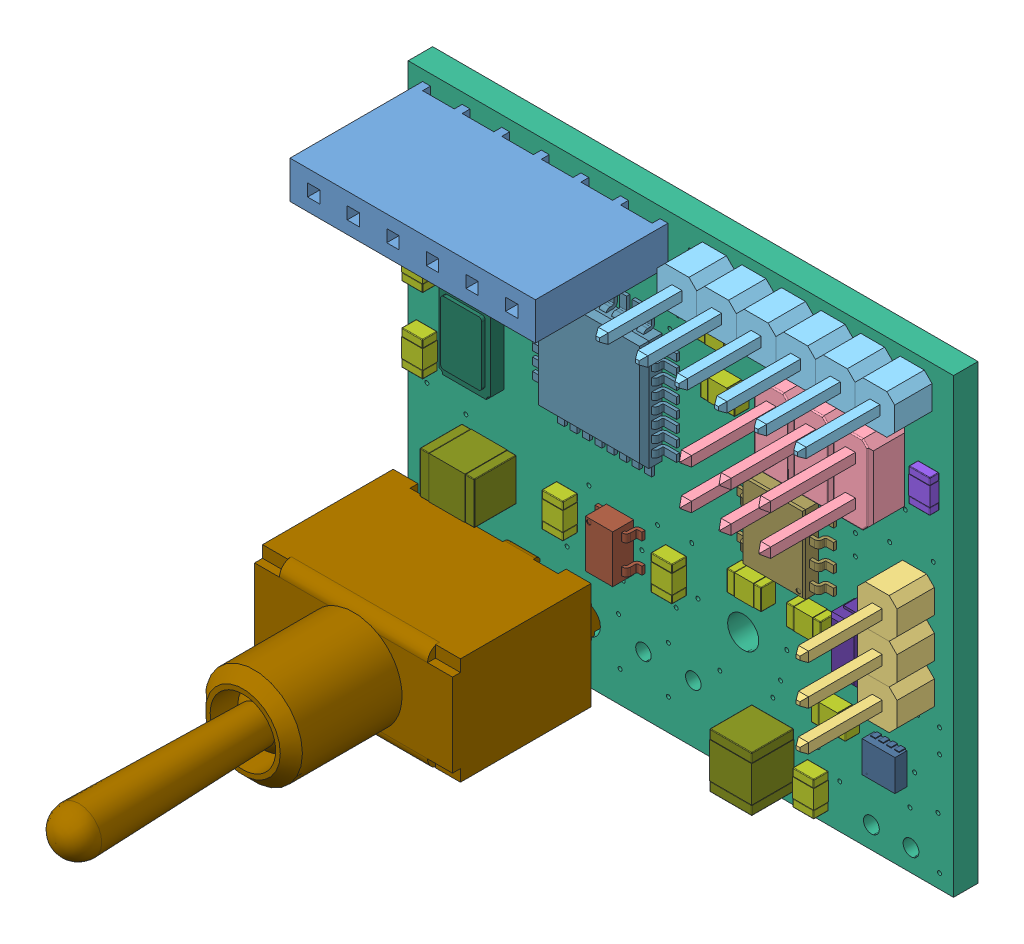
SolidWorks assembly vehicle, configuration Default. Lengths in mm.
Overall size (35 29 34.79).
44 component instances, 17 part files, 0 mates.
Components (placement in the parent):
- vehicle.step-1: vehicle.step [Default] at origin size (35 29 34.79)
  - PCB Component.step-1: PCB Component.step [Default] at origin size (35 29 34.79)
    - HM-10.step-1: HM-10.step [Default] at (8.8 27.1 1.57) x (0 1 0) z (0 0 1) size (2.41 15.75 11.15)
      - _SSW-106-01-S-S_terminal.step-1: _SSW-106-01-S-S_terminal.step [Default] x (0 -1 0) z (-1 0 0) size (15.75 8.51 2.41)
      - _SSW-106-01-S-S_pin.step-1: _SSW-106-01-S-S_pin.step [Default] at (0 0 -2.6416) x (0 -1 0) z (-1 0 0) size (13.74 3.66 1.22)
    - MG90S.step-1: MG90S.step [Default] at (32.5 13.3 1.57) x (0 -1 0) z (0 0 1) size (7.62 2.54 10.67)
      - P(B,C)C01SAAN (1).step-1: P(B,C)C01SAAN (1).step [Default] at (-2.54 0 0) x (1 0 0) z (0 -1 0) size (2.54 10.67 2.54)
      - P(B,C)C01SAAN (1).step-2: P(B,C)C01SAAN (1).step [Default] x (-1 0 0) z (0 1 0) size (2.54 10.67 2.54)
      - P(B,C)C01SAAN (1).step-3: P(B,C)C01SAAN (1).step [Default] at (2.54 0 0) x (1 0 0) z (0 -1 0) size (2.54 10.67 2.54)
    - AVRISP.step-1: AVRISP.step [Default] at (28.2 22.4 1.57) size (7.62 5.08 11.29)
      - Dual TH withbump format.step-1: Dual TH withbump format.step [Default] at (-2.5 0 0) x (1 0 0) z (0 -1 0) size (2.54 11.29 5.08)
      - Dual TH withbump format.step-2: Dual TH withbump format.step [Default] at (0.04 0 0) x (-1 0 0) z (0 1 0) size (2.54 11.29 5.08)
      - Dual TH withbump format.step-3: Dual TH withbump format.step [Default] at (2.58 0 0) x (1 0 0) z (0 -1 0) size (2.54 11.29 5.08)
    - FTDI.step-1: FTDI.step [Default] at (26 27.1 1.57) size (15.24 2.54 10.67)
      - P(B,C)C01SAAN.step-1: P(B,C)C01SAAN.step [Default] at (-6.35 0 0) x (1 0 0) z (0 -1 0) size (2.54 10.67 2.54)
      - P(B,C)C01SAAN.step-2: P(B,C)C01SAAN.step [Default] at (-3.81 0 0) x (-1 0 0) z (0 1 0) size (2.54 10.67 2.54)
      - P(B,C)C01SAAN.step-3: P(B,C)C01SAAN.step [Default] at (-1.27 0 0) x (1 0 0) z (0 -1 0) size (2.54 10.67 2.54)
      - P(B,C)C01SAAN.step-4: P(B,C)C01SAAN.step [Default] at (1.27 0 0) x (-1 0 0) z (0 1 0) size (2.54 10.67 2.54)
      - P(B,C)C01SAAN.step-5: P(B,C)C01SAAN.step [Default] at (3.81 0 0) x (1 0 0) z (0 -1 0) size (2.54 10.67 2.54)
      - P(B,C)C01SAAN.step-6: P(B,C)C01SAAN.step [Default] at (6.35 0 0) x (-1 0 0) z (0 1 0) size (2.54 10.67 2.54)
    - Board.step-1: Board.step [Default] at origin size (35 29 1.57)
    - 1uF_25V.step-1: 1uF_25V.step [Default] at (1.2 13.8 1.57) x (0 -1 0) z (0 0 1) size (2.2 1.35 0.95)
    - 1uF_25V.step-2: 1uF_25V.step [Default] at (20.6 24.4 1.57) size (2.2 1.35 0.95)
    - 1uF_25V.step-3: 1uF_25V.step [Default] at (22.5 11.3 1.57) size (2.2 1.35 0.95)
    - 1uF_25V.step-4: 1uF_25V.step [Default] at (10.2 9.3 1.57) x (0 -1 0) z (0 0 1) size (2.2 1.35 0.95)
    - 1uF_25V.step-5: 1uF_25V.step [Default] at (17.2 9.3 1.57) x (0 -1 0) z (0 0 1) size (2.2 1.35 0.95)
    - 1uF_25V.step-6: 1uF_25V.step [Default] at (27.9 6.8 1.57) x (-1 0 0) z (0 0 1) size (2.2 1.35 0.95)
    - 1uF_25V.step-7: 1uF_25V.step [Default] at (26.3 1.9 1.57) x (0 1 0) z (0 0 1) size (2.2 1.35 0.95)
    - 10K.step-1: 10K.step [Default] at (33.4 22.1 1.57) x (0 1 0) z (0 0 1) size (2.1 1.35 0.6)
    - 5A_28V.step-1: 5A_28V.step [Default] at (6.7 3.7 1.57) x (0 1 0) z (0 0 1) size (7.08 12.71 34.79)
    - DRV8838D 1.8A.step-1: DRV8838D 1.8A.step [Default] at (31 5.7 1.57) x (0 1 0) z (0 0 1) size (2.11 2.11 0.81)
    - MCP1802T-500 300mA_5V.step-1: MCP1802T-500 300mA_5V.step [Default] at (13.7 9.3 1.57) size (3 3.05 1.45)
    - BD60GC0WEFJ 1A_6V.step-1: BD60GC0WEFJ 1A_6V.step [Default] at (24.4 15.2 1.57) x (-1 0 0) z (0 0 1) size (6.2 5 1)
    - 1uF_25V.step-8: 1uF_25V.step [Default] at (26.3 11.3 1.57) x (-1 0 0) z (0 0 1) size (2.2 1.35 0.95)
    - 1uF_25V.step-9: 1uF_25V.step [Default] at (1.2 18.6 1.57) x (0 1 0) z (0 0 1) size (2.2 1.35 0.95)
    - 1uF_25V.step-10: 1uF_25V.step [Default] at (4.8 20.3 1.57) x (-1 0 0) z (0 0 1) size (2.2 1.35 0.95)
    - 1uF_25V.step-11: 1uF_25V.step [Default] at (4.8 22.5 1.57) x (-1 0 0) z (0 0 1) size (2.2 1.35 0.95)
    - 2PT_GND_TIE.step-1: 2PT_GND_TIE.step [Default] at (19.1 1.8 0) x (-1 0 0) z (0 0 -1) size (1.68 0.41 0.1)
    - ATMEGA328p.step-1: ATMEGA328p.step [Default] at (12.8 18.5 1.57) size (9.25 9.25 1.2)
    - 16 MHz.step-1: 16 MHz.step [Default] at (4.5 16.1 1.57) x (0 -1 0) z (0 0 1) size (5.1 3.3 1.1)
    - 100uF_16V.step-1: 100uF_16V.step [Default] at (23.4 2.5 1.57) x (0 1 0) z (0 0 1) size (3.5 2.7 2.7)
    - 100uF_16V.step-2: 100uF_16V.step [Default] at (5.2 9.2 1.57) x (-1 0 0) z (0 0 1) size (3.5 2.7 2.7)
    - 10uF_16V.step-1: 10uF_16V.step [Default] at (29.7 11.9 1.57) x (0 -1 0) z (0 0 1) size (3.7 1.8 1.8)
    - 1uF_25V.step-12: 1uF_25V.step [Default] at (20.8 21.3 1.57) size (2.2 1.35 0.95)
